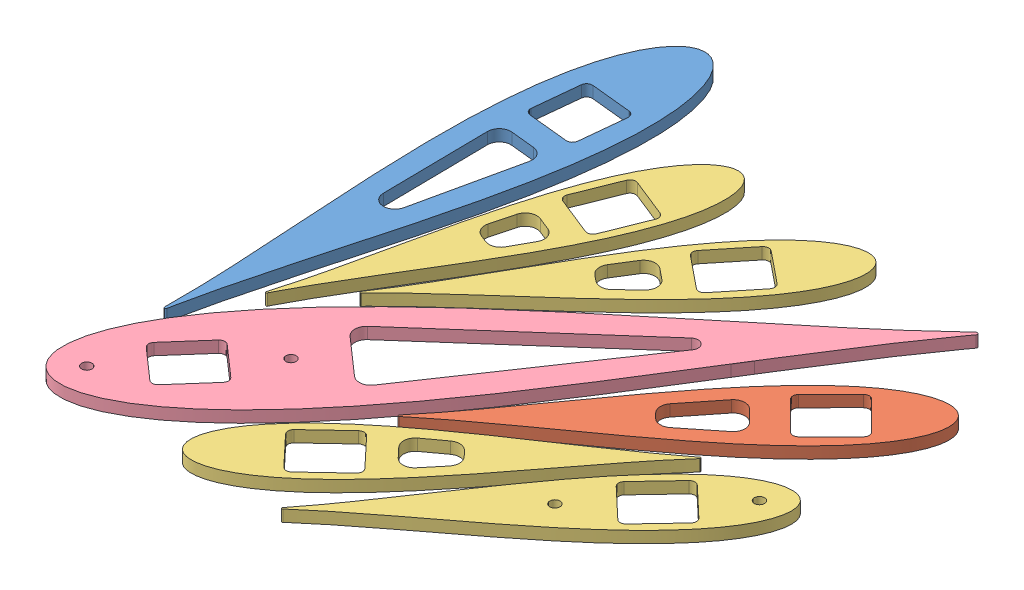
SolidWorks assembly layout, configuration Default. Lengths in mm.
Overall size (318.83 5.08 352.13).
8 component instances, 5 part files, 7 mates.
Components (placement in the parent):
- sheet_stock-2: sheet_stock [Default] at origin (suppressed, hidden)
- Keel_Rib1_Wide-1: Keel_Rib1_Wide [Default] at (33.6367 10.5537 -271.117) x (-0.101457 0 0.99484) z (0 -1 0) size (261.7 85.81 5.08)
- Keel_Rib2_Wide-1: Keel_Rib2_Wide [Default] at (226.5996 10.5537 -188.5903) x (-0.706655 0 0.707558) z (0 -1 0) size (209.67 68.75 5.08)
- Keel_streamline_rib_wide-1: Keel_streamline_rib_wide [Lightening] at (149.7662 10.5537 -229.19) x (-0.629578 0 0.776937) z (0 -1 0) size (194.14 63.66 5.08)
- Keel_streamline_rib_wide-2: Keel_streamline_rib_wide [Lightening] at (87.6862 10.5537 -232.8588) x (-0.371593 0 0.928396) z (0 -1 0) size (194.14 63.66 5.08)
- Keel_streamline_rib_wide-3: Keel_streamline_rib_wide [Lightening] at (68.9782 10.5537 -5.6776) x (0.728128 0 -0.685441) z (0 -1 0) size (194.14 63.66 5.08)
- Keel_streamline_rib_wide-4: Keel_streamline_rib_wide [Default] at (223.9908 10.5537 -121.8331) x (-0.687045 0 0.726615) z (0 -1 0) size (194.14 63.66 5.08)
- Keel_MasterRib_Wide-2: Keel_MasterRib_Wide [Default] at (8.1665 5.4737 -6.6073) x (0.660845 0 -0.750522) z (0 1 0) size (349.91 115.05 5.08)
Mates (geometry in assembly coordinates):
- Coincident2: coincident anti-aligned: plane of sheet_stock-2 through (0 5.4737 0) normal (0 1 0); plane of Keel_Rib1_Wide-1 through (33.6367 5.4737 -271.117) normal (0 -1 0)
- Coincident3: coincident anti-aligned: plane of sheet_stock-2 through (0 5.4737 0) normal (0 1 0); plane of Keel_streamline_rib_wide-1 through (149.7662 5.4737 -229.19) normal (0 -1 0)
- Coincident4: coincident anti-aligned: plane of sheet_stock-2 through (0 5.4737 0) normal (0 1 0); plane of Keel_Rib2_Wide-1 through (226.5996 5.4737 -188.5903) normal (0 -1 0)
- Coincident5: coincident anti-aligned: plane of sheet_stock-2 through (0 5.4737 0) normal (0 1 0); plane of Keel_streamline_rib_wide-2 through (87.6862 5.4737 -232.8588) normal (0 -1 0)
- Coincident6: coincident anti-aligned: plane of sheet_stock-2 through (0 5.4737 0) normal (0 1 0); plane of Keel_streamline_rib_wide-3 through (68.9782 5.4737 -5.6776) normal (0 -1 0)
- Coincident7: coincident anti-aligned: plane of sheet_stock-2 through (0 5.4737 0) normal (0 1 0); plane of Keel_streamline_rib_wide-4 through (223.9908 5.4737 -121.8331) normal (0 -1 0)
- Coincident8: coincident anti-aligned: plane of sheet_stock-2 through (0 5.4737 0) normal (0 1 0); plane of Keel_MasterRib_Wide-2 through (8.1665 5.4737 -6.6073) normal (0 -1 0)
